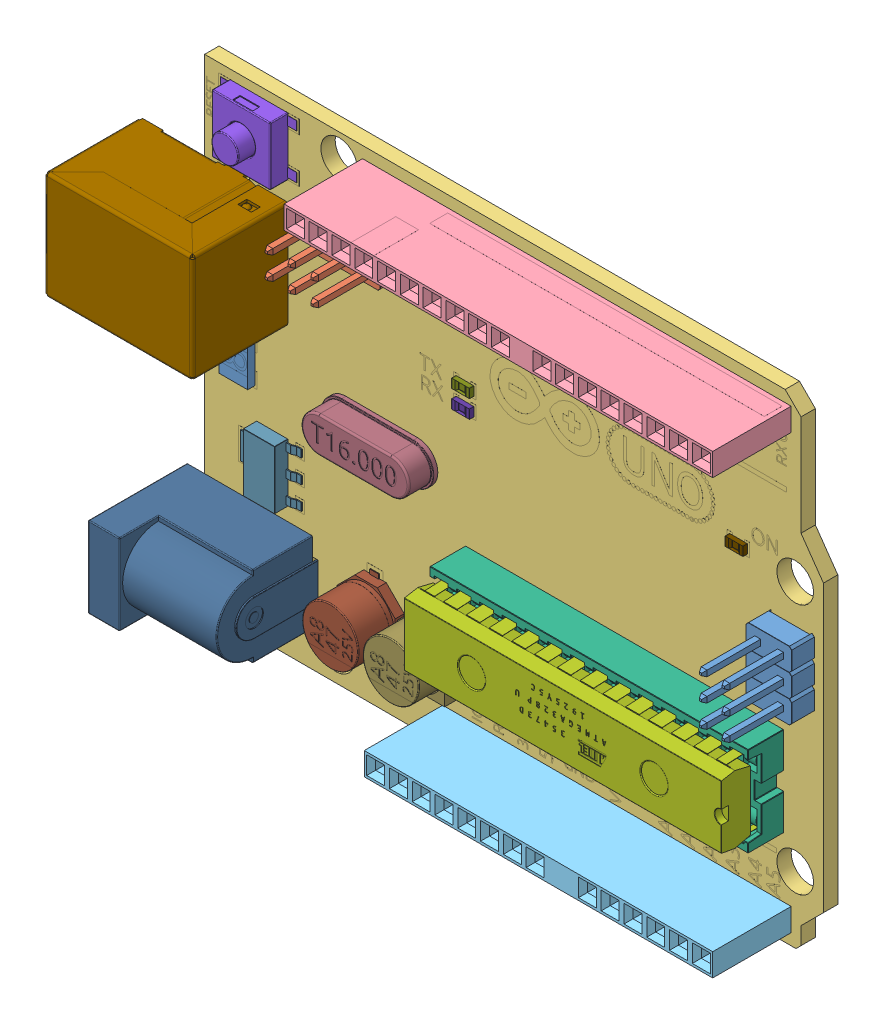
SolidWorks assembly Ardi_UNO.STEP, configuration Default. Lengths in mm.
Overall size (76.36 53.4 14.04).
19 component instances, 19 part files, 0 mates.
Components (placement in the parent):
- Pins_3fach_q_001.STEP-1: Pins_3fach_q_001.STEP [Default] at (64.19 -23.29 3.21) size (5.08 7.62 11.94)
- Pins_3fach_q_002.STEP-1: Pins_3fach_q_002.STEP [Default] at (15.78 -9.32 3.21) x (0 1 0) z (0 0 1) size (5.08 7.62 11.94)
- Ardi_UNO_Platine_001.STEP-1: Ardi_UNO_Platine_001.STEP [Default] at origin size (69 53.4 1.61)
- Headers_digital_001.STEP-1: Headers_digital_001.STEP [Default] at origin size (47.8 2.55 10.95)
- Headers_Analog_001.STEP-1: Headers_Analog_001.STEP [Default] at origin size (38.85 2.55 10.95)
- atmega328_socket_001.STEP-1: atmega328_socket_001.STEP [Default] at origin size (35.5 10 6.2)
- atmega328_001.STEP-1: atmega328_001.STEP [Default] at origin size (35.36 8.18 5.99)
- resetButton UNO_001.STEP-1: resetButton UNO_001.STEP [Default] at origin size (8.5 6.5 3.8)
- USB_typeB_001.STEP-1: USB_typeB_001.STEP [Default] at (8.29 -16.56 3.2) x (0 -1 0) z (0 0 1) size (12.06 16.98 13.98)
- Stromanschluss_arduino UNO_001.STEP-1: Stromanschluss_arduino UNO_001.STEP [Default] at origin size (14.2 9.2 13)
- Kondensator_A8-47-25V_001.STEP-1: Kondensator_A8-47-25V_001.STEP [Default] at (-0.25 0 0) size (6.5 7.5 5)
- Kondensator_A8-47-25V_002.STEP-1: Kondensator_A8-47-25V_002.STEP [Default] at (6.5 0 0) size (6.5 7.5 5)
- Quarz_Arduino_16_001.STEP-1: Quarz_Arduino_16_001.STEP [Default] at origin size (12.5 4.5 5.2)
- Transistor Arduino UNO_001.STEP-1: Transistor Arduino UNO_001.STEP [Default] at origin size (6.8 6.5 1.6)
- LED Arduino UNO gelb_001.STEP-1: LED Arduino UNO gelb_001.STEP [Default] at origin size (2 1 0.5)
- LED Arduino UNO gelb_002.STEP-1: LED Arduino UNO gelb_002.STEP [Default] at (0 -6 0) size (2 1 0.5)
- LED Arduino UNO gelb_003.STEP-1: LED Arduino UNO gelb_003.STEP [Default] at (0 -8 0) size (2 1 0.5)
- LED Arduino UNO gr__n_001.STEP-1: LED Arduino UNO gr__n_001.STEP [Default] at (30.5 -6 0) size (2 1 0.5)
- achterTeil_001.STEP-1: achterTeil_001.STEP [Default] at origin size (3.2 4.7 0.8)
